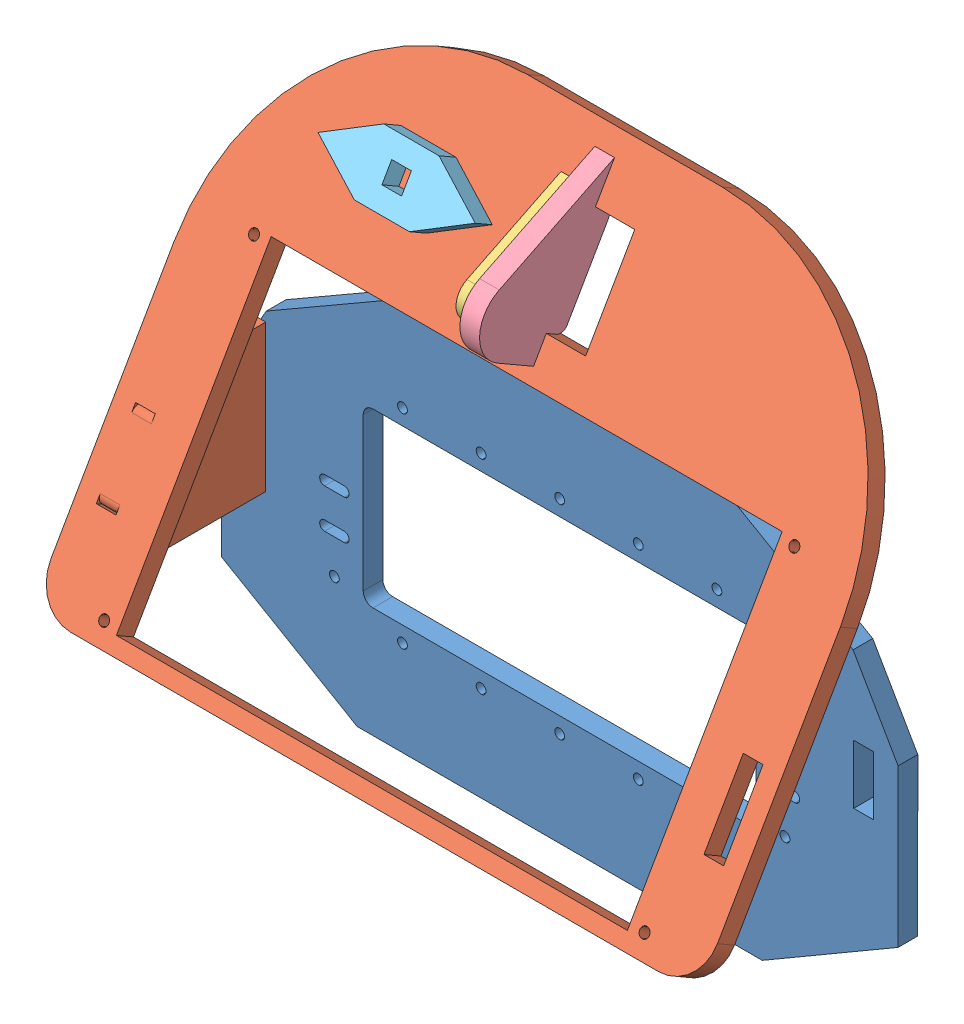
SolidWorks assembly sketch_assem, configuration Default. Lengths in mm.
Overall size (218.69 188.88 84.14).
7 component instances, 7 part files, 19 mates.
Components (placement in the parent):
- lasercut_pattern-1: lasercut_pattern [Default] at (-120.524 102.5444 443.3714) size (554.69 514.35 0) (hidden)
- robot_motor_end_cap-1: robot_motor_end_cap [Default] at origin size (218.69 126.98 0)
- Part2^sketch_assem-1: Part2^sketch_assem [Default] at origin size (218.69 126.98 6.35) (virtual)
- Part6^sketch_assem-1: Part6^sketch_assem [Default] at (13.97 0 0) x (0 0 1) z (-1 0 0) size (89.64 148.91 215.4) (virtual)
- Part8^sketch_assem-1: Part8^sketch_assem [Default] at (38.1 0 0) x (0 0 -1) z (1 0 0) size (44.96 33.42 6.35) (virtual)
- Part9^sketch_assem-1: Part9^sketch_assem [Default] at (44.45 0 0) x (0 0 -1) z (1 0 0) size (43.61 45.33 6.35) (virtual)
- Part10^sketch_assem-1: Part10^sketch_assem [Default] at (13.97 9.0996 15.761) x (1 0 0) z (0 0.5 0.866025) size (50.8 19.05 6.35) (virtual)
Mates (geometry in assembly coordinates):
- InPlace1: in place: plane of ? through (0 0 0) normal (0 0 1); moOrthogonalPlaneRef_w of ? through (0 0 0) normal (0 1 0); plane of ? through (0 0 0) normal (1 0 0); unknown of ?
- Coincident1: coincident aligned: 
- Coincident2: coincident aligned: plane of robot_motor_end_cap-1 through (0 0 0) normal (0 1 0)
- Coincident3: coincident anti-aligned: plane of robot_motor_end_cap-1 through (0 0 0) normal (1 0 0)
- Coincident4: coincident anti-aligned: plane of Part2^sketch_assem-1 through (-50.55 -50.6062 6.35) normal (1 0 0); plane of Part6^sketch_assem-1 through (-50.55 -50.6062 6.35) normal (-1 0 0)
- Coincident5: coincident anti-aligned: plane of Part2^sketch_assem-1 through (0 0 6.35) normal (0 0 1); plane of Part6^sketch_assem-1 through (-125.1382 -50.6062 6.35) normal (0 0 -1)
- Coincident6: coincident anti-aligned: plane of Part2^sketch_assem-1 through (-50.55 -50.6062 6.35) normal (0 -1 0); plane of Part6^sketch_assem-1 through (-125.1382 -50.6062 6.35) normal (0 1 0)
- InPlace3: in place: plane of Part6^sketch_assem-1 through (38.1 45.4029 -5.1987) normal (1 0 0); plane of Part8^sketch_assem-1 through (38.1 0 0) normal (1 0 0); plane of Part6^sketch_assem-1 through (38.1 45.4029 -5.1987) normal (1 0 0); plane of Part8^sketch_assem-1 through (38.1 0 0) normal (0 1 0); plane of Part6^sketch_assem-1 through (38.1 45.4029 -5.1987) normal (1 0 0); plane of Part8^sketch_assem-1 through (38.1 0 0) normal (0 0 -1); plane of Part6^sketch_assem-1 through (38.1 45.4029 -5.1987) normal (1 0 0); unknown of Part8^sketch_assem-1
- Coincident7: coincident aligned: plane of Part6^sketch_assem-1; plane of Part8^sketch_assem-1
- Coincident8: coincident aligned: moOrthogonalPlaneRef_w of Part6^sketch_assem-1 through (38.1 0 0) normal (0 1 0); plane of Part8^sketch_assem-1 through (38.1 0 0) normal (0 1 0)
- Coincident9: coincident anti-aligned: moOrthogonalPlaneRef_w of Part6^sketch_assem-1 through (38.1 0 0) normal (0 0 1); plane of Part8^sketch_assem-1 through (38.1 0 0) normal (0 0 -1)
- InPlace4: in place: plane of Part8^sketch_assem-1 through (44.45 18.2013 6.1068) normal (1 0 0); plane of Part9^sketch_assem-1 through (44.45 0 0) normal (1 0 0); plane of Part8^sketch_assem-1 through (44.45 18.2013 6.1068) normal (1 0 0); plane of Part9^sketch_assem-1 through (44.45 0 0) normal (0 1 0); plane of Part8^sketch_assem-1 through (44.45 18.2013 6.1068) normal (1 0 0); plane of Part9^sketch_assem-1 through (44.45 0 0) normal (0 0 -1); plane of Part8^sketch_assem-1 through (44.45 18.2013 6.1068) normal (1 0 0); unknown of Part9^sketch_assem-1
- Coincident10: coincident aligned: plane of Part8^sketch_assem-1; plane of Part9^sketch_assem-1
- Coincident11: coincident aligned: moOrthogonalPlaneRef_w of Part8^sketch_assem-1 through (44.45 0 0) normal (0 1 0); plane of Part9^sketch_assem-1 through (44.45 0 0) normal (0 1 0)
- Coincident12: coincident anti-aligned: moOrthogonalPlaneRef_w of Part8^sketch_assem-1 through (44.45 0 0) normal (0 0 1); plane of Part9^sketch_assem-1 through (44.45 0 0) normal (0 0 -1)
- InPlace5: in place: plane of Part6^sketch_assem-1 through (-125.1382 -56.1959 53.4594) normal (0 0.5 0.866025); plane of ? through (0 9.0996 15.761) normal (0 0.5 0.866025); plane of Part6^sketch_assem-1 through (-125.1382 -56.1959 53.4594) normal (0 0.5 0.866025); plane of ? through (0 9.0996 15.761) normal (0 0.866025 -0.5); plane of Part6^sketch_assem-1 through (-125.1382 -56.1959 53.4594) normal (0 0.5 0.866025); plane of ? through (0 9.0996 15.761) normal (1 0 0); plane of Part6^sketch_assem-1 through (-125.1382 -56.1959 53.4594) normal (0 0.5 0.866025); unknown of Part10^sketch_assem-1
- Coincident13: coincident aligned: plane of Part6^sketch_assem-1; plane of Part10^sketch_assem-1
- Coincident14: coincident aligned: moOrthogonalPlaneRef_w of Part6^sketch_assem-1 through (13.97 9.0996 15.761) normal (0 0.866025 -0.5); plane of Part10^sketch_assem-1 through (13.97 9.0996 15.761) normal (0 0.866025 -0.5)
- Coincident15: coincident anti-aligned: moOrthogonalPlaneRef_w of Part6^sketch_assem-1 through (13.97 9.0996 15.761) normal (-1 0 0); plane of Part10^sketch_assem-1 through (13.97 9.0996 15.761) normal (1 0 0)
